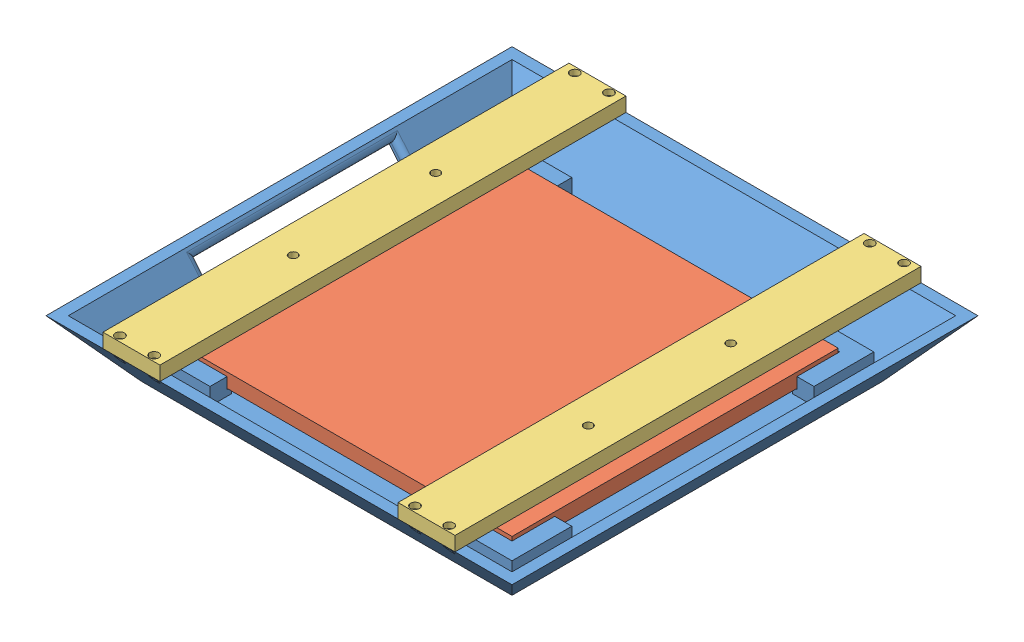
SolidWorks assembly bluetooth_radome_ASSEMBLY, configuration Default. Lengths in mm.
Overall size (163.56 25 163.57).
4 component instances, 3 part files, 10 mates.
Components (placement in the parent):
- aircraft_BLE_radome-1: aircraft_BLE_radome [Default] at origin size (163.56 20 163.56)
- BLE_Soc_stand-in-1: BLE_Soc_stand-in [Default] at (-0.0407 5.1 -0.05) size (114.5 5 114.5)
- radome_crossbar-1: radome_crossbar [Default] at (-51.782 20 0.003) x (0 0 -1) z (1 0 0) size (163.57 5 20)
- radome_crossbar-2: radome_crossbar [Default] at (51.782 20 0.003) x (0 0 -1) z (1 0 0) size (163.57 5 20)
Mates (geometry in assembly coordinates):
- Coincident1: coordinate: point of aircraft_BLE_radome-1
- Coincident2: coincident anti-aligned: plane of aircraft_BLE_radome-1 through (0 5.1 0) normal (0 1 0); plane of BLE_Soc_stand-in-1 through (-0.0407 5.1 -0.05) normal (0 -1 0)
- Distance1: distance = 0.3 mm anti-aligned: plane of BLE_Soc_stand-in-1 through (-57.2907 10.1 57.2) normal (0 0 1); plane of aircraft_BLE_radome-1 through (0 9 57.5) normal (0 0 -1)
- Coincident8: coincident anti-aligned: plane of aircraft_BLE_radome-1 through (0 20 0) normal (0 1 0); plane of radome_crossbar-1 through (-51.782 20 0.003) normal (0 -1 0)
- Concentric3: concentric anti-aligned: cylinder of aircraft_BLE_radome-1 through (-45.782 -1.65 -79.822) axis (0 1 0) radius 1; cylinder of radome_crossbar-1 through (-45.782 25 -79.822) axis (0 -1 0) radius 1
- Parallel2: parallel aligned: plane of aircraft_BLE_radome-1 through (0 20 0) normal (0 1 0); plane of radome_crossbar-1 through (-51.782 25 0.003) normal (0 1 0)
- Parallel3: parallel: line of aircraft_BLE_radome-1 through (-81.782 20 81.782) axis (1 0 0); plane of radome_crossbar-1 through (-41.782 25 81.788) normal (0 0 1)
- Concentric4: concentric: cylinder of aircraft_BLE_radome-1 through (45.782 10 -79.822) axis (0 1 0) radius 1; cylinder of radome_crossbar-2 through (45.782 25 -79.822) axis (0 -1 0) radius 1
- Coincident10: coincident: plane of aircraft_BLE_radome-1 through (0 20 0) normal (0 1 0); plane of radome_crossbar-2 through (51.782 20 0.003) normal (0 -1 0)
- Parallel5: parallel aligned: line of aircraft_BLE_radome-1 through (-81.782 20 81.782) axis (1 0 0); line of radome_crossbar-2 through (41.782 25 81.788) axis (1 0 0)
